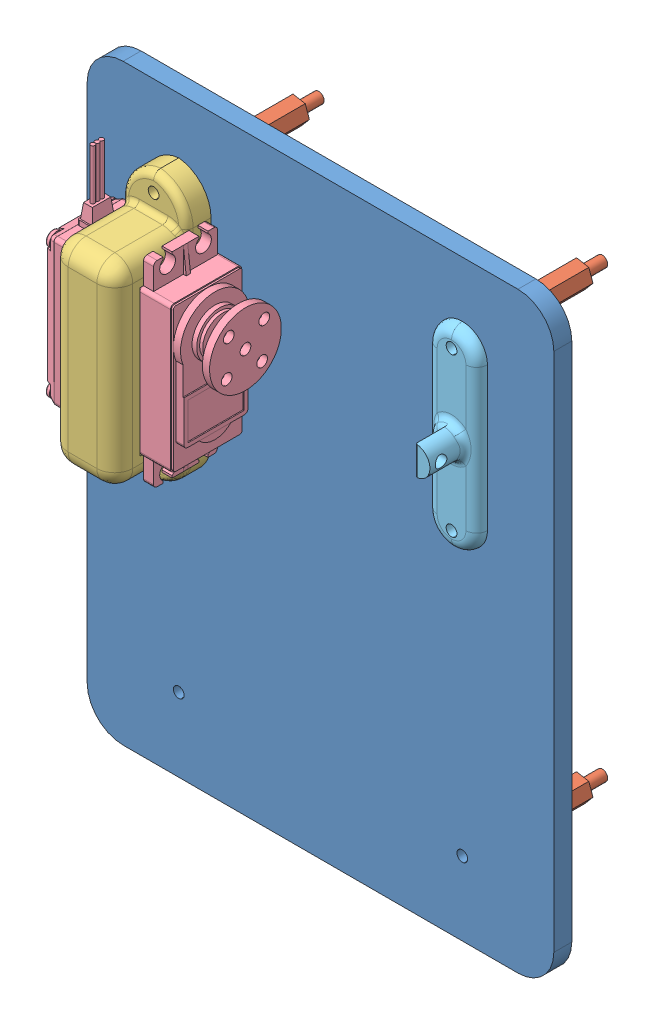
SolidWorks assembly Garra, configuration Valor predeterminado. Lengths in mm.
Overall size (130 165 65.81).
8 component instances, 5 part files, 42 mates.
Components (placement in the parent):
- Chassi-Cima-1: Chassi-Cima [Valor predeterminado] at (-114.9775 80.2366 -211.3169) size (130 165 5)
- Standoff-Nylon-5: Standoff-Nylon [Valor predeterminado] at (-80.3866 195.128 -239.3169) size (6.82 6.52 34)
- Standoff-Nylon-6: Standoff-Nylon [Valor predeterminado] at (-159.3866 195.128 -239.3169) size (6.82 6.52 34)
- Standoff-Nylon-7: Standoff-Nylon [Valor predeterminado] at (-159.3866 71.128 -239.3169) size (6.82 6.52 34)
- Standoff-Nylon-8: Standoff-Nylon [Valor predeterminado] at (-80.3866 71.128 -239.3169) size (6.82 6.52 34)
- Suporte-Servo-MG-1: Suporte-Servo-MG [Valor predeterminado] at (-139.6947 160.1002 -194.0213) x (0 -1 0) z (-1 0 0) size (74.72 26.81 18)
- Servo-MG-995-2: Servo-MG-995 [Valor predeterminado] at (-149.3652 229.2427 -200.4443) x (0 0 -1) z (0 -1 0) size (20 46.48 67)
- Mancal-1: Mancal [Valor predeterminado] at (-65.0421 180.5269 -206.3169) x (0 -1 0) z (0 0 1) size (54 14 13)
Mates (geometry in assembly coordinates):
- Concêntrico4: concentric anti-aligned: circle of Chassi-Cima-1; circle of Standoff-Nylon-5
- Coincidente8: coincident anti-aligned: plane of Chassi-Cima-1 through (-164.1947 205.7406 -212.0857) normal (0 0 -1); plane of Standoff-Nylon-5 through (-80.3866 202.0259 -212.0857) normal (0 0 1)
- Concêntrico5: concentric anti-aligned: circle of Chassi-Cima-1; circle of Standoff-Nylon-6
- Coincidente10: coincident anti-aligned: plane of Chassi-Cima-1 through (-164.1947 205.7406 -212.0857) normal (0 0 -1); plane of Standoff-Nylon-6 through (-159.3866 202.0259 -212.0857) normal (0 0 1)
- Concêntrico6: concentric anti-aligned: circle of Chassi-Cima-1; circle of Standoff-Nylon-7
- Coincidente12: coincident anti-aligned: plane of Chassi-Cima-1 through (-164.1947 205.7406 -212.0857) normal (0 0 -1); plane of Standoff-Nylon-7 through (-159.3866 78.0259 -212.0857) normal (0 0 1)
- Concêntrico7: concentric anti-aligned: circle of Chassi-Cima-1; circle of Standoff-Nylon-8
- Coincidente14: coincident anti-aligned: plane of Chassi-Cima-1 through (-164.1947 205.7406 -212.0857) normal (0 0 -1); plane of Standoff-Nylon-8 through (-80.3866 78.0259 -212.0857) normal (0 0 1)
- Coincidente20: coincident anti-aligned: plane of Chassi-Cima-1 through (-156.9803 36.4113 -18.6694) normal (0 1 0); plane of ? through (-155.9895 36.4113 4.227) normal (0 -1 0)
- Coincidente21: coincident anti-aligned: plane of Chassi-Cima-1 through (-139.4803 36.4113 -18.6694) normal (1 0 0); plane of ? through (-139.4803 36.4113 -18.6694) normal (-1 0 0)
- Coincidente22: coincident aligned: plane of Chassi-Cima-1 through (-224.4803 91.4113 -23.6694) normal (0 0 -1); plane of ? through (-139.4803 36.4113 -23.6694) normal (0 0 -1)
- Coincidente26: coincident anti-aligned: plane of Chassi-Cima-1 through (-106.4803 26.4113 -18.6694) normal (0 -1 0); plane of ? through (-106.4803 26.4113 -18.6694) normal (0 1 0)
- Coincidente27: coincident anti-aligned: plane of Chassi-Cima-1 through (-106.4803 1.4113 -18.6694) normal (-1 0 0); plane of ? through (-106.4803 -33.5887 21.3306) normal (1 0 0)
- Coincidente28: coincident aligned: plane of Chassi-Cima-1 through (-224.4803 91.4113 -23.6694) normal (0 0 -1); plane of ? through (-106.4803 -53.5887 -23.6694) normal (0 0 -1)
- Coincidente32: coincident anti-aligned: plane of Chassi-Cima-1 through (-232.4803 26.4113 -18.6694) normal (0 -1 0); plane of ? through (-229.4803 26.4113 -18.6694) normal (0 1 0)
- Coincidente33: coincident anti-aligned: plane of Chassi-Cima-1 through (-229.4803 26.4113 -18.6694) normal (-1 0 0); plane of ? through (-229.4803 -33.5887 11.3306) normal (1 0 0)
- Coincidente34: coincident aligned: plane of Chassi-Cima-1 through (-224.4803 91.4113 -23.6694) normal (0 0 -1); plane of ? through (-229.4803 1.4113 -23.6694) normal (0 0 -1)
- Concêntrico8: concentric anti-aligned: circle of ?; circle of ?
- Concêntrico9: concentric anti-aligned: circle of ?; circle of ?
- Coincidente40: coincident anti-aligned: plane of ? through (-109.4803 -33.5887 21.3306) normal (-1 0 0); plane of ? through (-109.4803 -45.2137 18.7306) normal (1 0 0)
- Coincidente44: coincident anti-aligned: plane of ? through (-109.4803 -31.9637 -4.0194) normal (0 0 1); plane of ? through (-121.9803 -52.0137 -4.0194) normal (0 0 -1)
- Coincidente45: coincident anti-aligned: plane of ? through (-121.9803 -23.4758 23.3806) normal (1 0 0); plane of ? through (-121.9803 -52.0137 -4.0194) normal (-1 0 0)
- Coincidente46: coincident anti-aligned: plane of ? through (-121.9803 -45.2137 18.7306) normal (0 -1 0); plane of ? through (-109.4803 -45.2137 18.6806) normal (0 1 0)
- Coincidente47: coincident aligned: plane of Chassi-Cima-1 through (-234.4803 -53.5887 -18.6694) normal (-1 0 0); plane of ? through (-234.4803 71.2813 -8.6694) normal (-1 0 0)
- Coincidente48: coincident anti-aligned: plane of Chassi-Cima-1 through (-224.4803 91.4113 -18.6694) normal (0 0 1); plane of ? through (-197.6203 91.4113 -18.6694) normal (0 0 -1)
- Distância1: distance = 10 mm aligned: plane of ? through (-197.6203 91.4113 1.3306) normal (0 1 0); plane of Chassi-Cima-1 through (-224.4803 101.4113 -18.6694) normal (0 1 0)
- Coincidente56: coincident anti-aligned: plane of Chassi-Cima-1 through (-164.1947 205.7406 -207.0857) normal (0 0 1); plane of Suporte-Servo-MG-1 through (-157.6947 142.6406 -207.0857) normal (0 0 -1)
- Coincidente58: coincident anti-aligned: plane of Chassi-Cima-1 through (-200.5747 91.4113 -60.0337) normal (0 0 1); plane of ? through (-184.5747 -35.7473 -60.0337) normal (0 0 -1)
- Tangente1: tangent anti-aligned: cylinder of Suporte-Servo-MG-1 through (-189.5747 83.9113 -33.2237) axis (0 0 -1) radius 5; plane of ? through (-184.5747 -15.4473 -50.1337) normal (-1 0 0)
- Coincidente60: coincident aligned: plane of Suporte-Servo-MG-1 through (-202.5747 81.9113 -40.2237) normal (0 -1 0); plane of ? through (-184.5747 81.9113 -60.0337) normal (0 -1 0)
- Concêntrico12: concentric aligned: circle of Standoff-Nylon-5; circle of ?
- Concêntrico13: concentric anti-aligned: circle of Chassi-Cima-1; circle of ?
- Coincidente63: coincident anti-aligned: plane of Chassi-Cima-1 through (-204.5527 141.3435 -74.9786) normal (0 0 1); plane of ? through (-123.0583 138.1831 -74.9786) normal (0 0 -1)
- Concêntrico14: concentric anti-aligned: circle of Chassi-Cima-1; circle of Mancal-1
- Coincidente67: coincident anti-aligned: plane of Chassi-Cima-1 through (-164.1947 205.7406 -207.0857) normal (0 0 1); plane of Mancal-1 through (-65.0421 187.4248 -207.0857) normal (0 0 -1)
- Concêntrico18: concentric anti-aligned: circle of Chassi-Cima-1; circle of Mancal-1
- Concêntrico19: concentric anti-aligned: circle of Standoff-Nylon-6; circle of Suporte-Servo-MG-1
- Concêntrico20: concentric aligned: circle of Servo-MG-995-2; circle of ?
- Coincidente71: coincident anti-aligned: plane of Servo-MG-995-2 through (-139.7499 161.7657 -160.8111) normal (1 0 0); plane of ? through (-139.7499 168.4357 -156.8111) normal (-1 0 0)
- Coincidente72: coincident: plane of Suporte-Servo-MG-1 through (-157.6947 176.3427 -186.5069) normal (0 -1 0); plane of Servo-MG-995-2 through (-126.3354 176.3427 -186.5069) normal (0 1 0)
- Coincidente73: coincident: plane of Suporte-Servo-MG-1 through (-157.6947 176.3427 -186.5069) normal (0 0 -1); plane of Servo-MG-995-2 through (-126.3354 176.3427 -186.5069) normal (0 0 1)
- Coincidente74: coincident anti-aligned: plane of Suporte-Servo-MG-1 through (-139.6947 160.1002 -194.0213) normal (1 0 0); plane of Servo-MG-995-2 through (-139.6947 156.0427 -196.4069) normal (-1 0 0)
